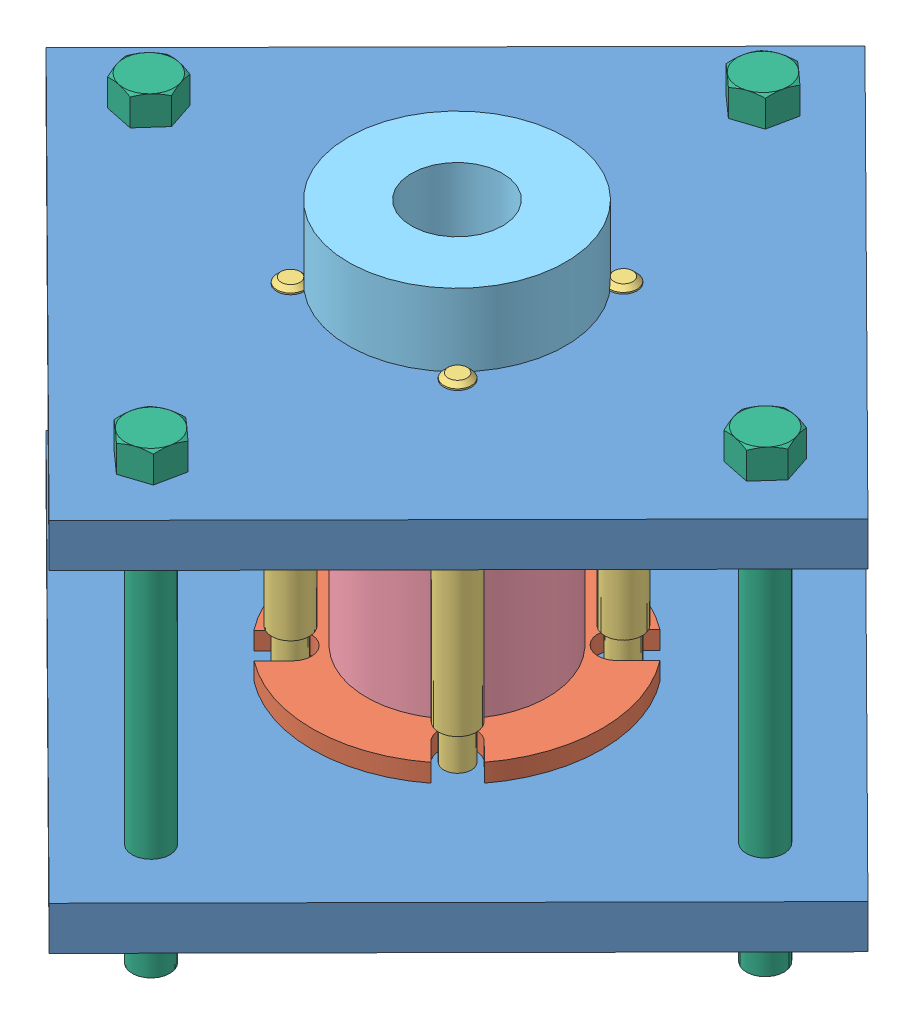
SolidWorks assembly Fixture Assembly, configuration Default. Lengths in mm.
Overall size (565.68 350 565.68).
18 component instances, 7 part files, 26 mates.
Components (placement in the parent):
- End Plate-1: End Plate [Default] at (-256.5859 237.5387 5.8322) x (0.704535 0 -0.70967) z (0.70967 0 0.704535) size (400 30 400)
- Disc-3: Disc [Default] at (-256.5859 280.0387 5.8322) x (0.704524 0 -0.70968) z (0 -1 0) size (198.33 198.31 12.5)
- Support Pin-1: Support Pin [Default] at (-313.8646 373.4308 63.5283) x (0.546131 0 0.8377) z (-0.8377 0 0.546131) size (26 263 26)
- Support Pin-5: Support Pin [Default] at (-314.2821 373.4308 -51.4465) x (-0.8377 0 0.546131) z (-0.546131 0 -0.8377) size (26 263 26)
- Support Pin-6: Support Pin [Default] at (-199.3073 373.4308 -51.8639) x (-0.546131 0 -0.8377) z (0.8377 0 -0.546131) size (26 263 26)
- Spacer-1: Spacer [Default] at (-256.5859 280.0387 5.8322) x (0.868128 0 -0.496341) z (0.496341 0 0.868128) size (125 138 125)
- Centre Pin-2: Centre Pin [Default] at (-256.5859 472.7787 5.8322) x (-0.189922 0 0.981799) z (0 -1 0) size (150 150 250)
- End Plate-3: End Plate [Default] at (-256.5859 466.5387 5.8322) x (0.704535 0 -0.70967) z (0.70967 0 0.704535) size (400 30 400)
- Disc-6: Disc [Default] at (-256.5859 466.5387 5.8322) x (0.704524 0 -0.70968) z (0 -1 0) size (198.33 198.31 12.5)
- Support Pin-8: Support Pin [Default] at (-198.8898 373.4308 63.1109) x (0.826173 0 0.563416) z (-0.563416 0 0.826173) size (26 263 26)
- Bolt-8: Bolt [Default] at (-255.8157 496.5387 217.9628) x (0.949756 0 -0.312993) z (0.312993 0 0.949756) size (40.41 320 35)
- Nut-8: Nut [Default] at (-255.8157 217.5387 217.9628) x (0.793726 0 0.608276) z (-0.608276 0 0.793726) size (35 20 30.31)
- Nut-9: Nut [Default] at (-44.4553 217.5387 5.062) x (0.608276 0 -0.793726) z (0.793726 0 0.608276) size (35 20 30.31)
- Nut-10: Nut [Default] at (-257.3562 217.5387 -206.2984) x (-0.793726 0 -0.608276) z (0.608276 0 -0.793726) size (35 20 30.31)
- Nut-11: Nut [Default] at (-468.7166 217.5387 6.6024) x (-0.608276 0 0.793726) z (-0.793726 0 -0.608276) size (35 20 30.31)
- Bolt-9: Bolt [Default] at (-44.4553 496.5387 5.062) x (-0.312993 0 -0.949756) z (0.949756 0 -0.312993) size (40.41 320 35)
- Bolt-10: Bolt [Default] at (-257.3562 496.5387 -206.2984) x (-0.949756 0 0.312993) z (-0.312993 0 -0.949756) size (40.41 320 35)
- Bolt-11: Bolt [Default] at (-468.7166 496.5387 6.6024) x (0.312993 0 0.949756) z (-0.949756 0 0.312993) size (40.41 320 35)
Mates (geometry in assembly coordinates):
- Concentric2: concentric: cylinder of End Plate-1 through (-256.5859 267.5387 5.8322) axis (0 -1 0) radius 50; cylinder of Disc-3 through (-256.5859 267.5387 5.8322) axis (0 1 0) radius 50
- Coincident2: coincident: plane of End Plate-1 through (-256.5859 267.5387 5.8322) normal (0 1 0); plane of Disc-3 through (-256.5859 267.5387 5.8322) normal (0 -1 0)
- Concentric3: concentric: cylinder of End Plate-1 through (-313.8646 267.5387 63.5283) axis (0 -1 0) radius 9.5; cylinder of Support Pin-1 through (-313.8646 500.5387 63.5283) axis (0 1 0) radius 9.5
- Coincident4: coincident aligned: plane of End Plate-1 through (-256.5859 237.5387 5.8322) normal (0 -1 0); plane of Support Pin-1 through (-310.3148 237.5387 68.9734) normal (0 -1 0)
- Concentric6: concentric: cylinder of End Plate-1 through (-256.5859 267.5387 5.8322) axis (0 -1 0) radius 50; cylinder of Spacer-1 through (-256.5859 418.0387 5.8322) axis (0 -1 0) radius 62.5
- Concentric7: concentric: cylinder of Spacer-1 through (-256.5859 418.0387 5.8322) axis (0 -1 0) radius 50; cylinder of Centre Pin-2 through (-256.5859 546.5387 5.8322) axis (0 1 0) radius 50
- Concentric8: concentric: cylinder of Centre Pin-2 through (-256.5859 546.5387 5.8322) axis (0 1 0) radius 50; cylinder of End Plate-3 through (-256.5859 496.5387 5.8322) axis (0 -1 0) radius 50
- Coincident6: coincident: plane of Support Pin-6 through (-199.3073 500.5387 -51.8639) normal (0 1 0); plane of End Plate-3 through (-256.5859 496.5387 5.8322) normal (0 1 0)
- Coincident7: coincident: plane of Centre Pin-2 through (-270.8301 496.5387 79.4671) normal (0 -1 0); plane of End Plate-3 through (-256.5859 496.5387 5.8322) normal (0 1 0)
- Concentric9: concentric aligned: cylinder of Centre Pin-2 through (-256.5859 546.5387 5.8322) axis (0 1 0) radius 50; cylinder of Disc-6 through (-256.5859 454.0387 5.8322) axis (0 1 0) radius 50
- Coincident8: coincident anti-aligned: plane of End Plate-3 through (-256.5859 466.5387 5.8322) normal (0 -1 0); plane of Disc-6 through (-256.5859 466.5387 5.8322) normal (0 1 0)
- Parallel1: parallel: plane of End Plate-1 through (-539.4268 267.5387 6.8592) normal (-0.70967 0 -0.704535); plane of End Plate-3 through (-539.4268 496.5387 6.8592) normal (-0.70967 0 -0.704535)
- Parallel3: parallel aligned: cylinder of Disc-3 through (-198.8097 267.5387 63.1886) axis (0 1 0) radius 13.0514; cylinder of Disc-6 through (-198.8097 454.0387 63.1886) axis (0 1 0) radius 13.0514
- Concentric12: concentric aligned: cylinder of Disc-3 through (-313.0806 267.5387 62.8298) axis (0 1 0) radius 12.9544; cylinder of Disc-6 through (-313.0806 454.0387 62.8298) axis (0 1 0) radius 12.9544
- Concentric15: concentric anti-aligned: cylinder of End Plate-1 through (-198.8898 267.5387 63.1109) axis (0 -1 0) radius 9.5; cylinder of Support Pin-8 through (-198.8898 500.5387 63.1109) axis (0 1 0) radius 9.5
- Width3: width: plane of Disc-3 through (-265.8012 267.5387 15.0959) normal (0.705251 0 -0.708958); plane of Disc-3 through (-247.4334 267.5387 -3.3888) normal (-0.704468 0 0.709736); cylinder of Support Pin-5 through (-314.2821 500.5387 -51.4465) axis (0 1 0) radius 9.5
- Coincident15: coincident aligned: plane of End Plate-1 through (-256.5859 237.5387 5.8322) normal (0 -1 0); plane of Support Pin-1 through (-310.3148 237.5387 68.9734) normal (0 -1 0)
- Coincident18: coincident aligned: plane of End Plate-1 through (-256.5859 237.5387 5.8322) normal (0 -1 0); plane of Support Pin-8 through (-193.5197 237.5387 66.7731) normal (0 -1 0)
- Coincident19: coincident anti-aligned: plane of Disc-3 through (-256.5859 280.0387 5.8322) normal (0 1 0); plane of Spacer-1 through (-256.5859 280.0387 5.8322) normal (0 -1 0)
- Concentric18: concentric anti-aligned: cylinder of End Plate-3 through (-255.8157 496.5387 217.9628) axis (0 -1 0) radius 13; cylinder of Bolt-8 through (-255.8157 196.5387 217.9628) axis (0 1 0) radius 13
- Coincident20: coincident anti-aligned: plane of End Plate-3 through (-256.5859 496.5387 5.8322) normal (0 1 0); plane of Bolt-8 through (-255.8157 496.5387 217.9628) normal (0 -1 0)
- Concentric19: concentric: cylinder of Bolt-8 through (-255.8157 196.5387 217.9628) axis (0 1 0) radius 13; cylinder of Nut-8 through (-255.8157 217.5387 217.9628) axis (0 1 0) radius 13
- Coincident21: coincident anti-aligned: plane of End Plate-1 through (-256.5859 237.5387 5.8322) normal (0 -1 0); plane of Nut-8 through (-255.8157 237.5387 217.9628) normal (0 1 0)
- Lock3: lock: unknown of End Plate-1; unknown of Nut-8
- Coincident24: coincident: plane of End Plate-3 through (-256.5859 496.5387 5.8322) normal (0 1 0); plane of Bolt-11 through (-468.7166 496.5387 6.6024) normal (0 -1 0)
- Lock4: lock: unknown of End Plate-3; unknown of Bolt-9
